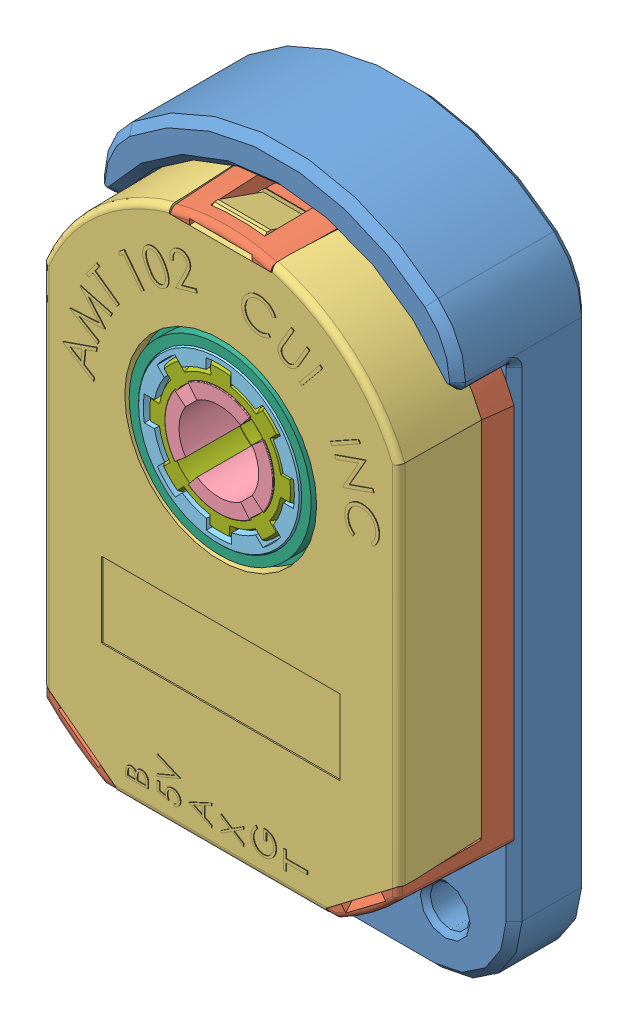
SolidWorks assembly AARL_Puppy_18_01_04_SlabAssembly2, configuration Default. Lengths in mm.
Overall size (36.33 55.03 18.35).
11 component instances, 10 part files, 3 mates.
Components (placement in the parent):
- AARL_Puppy_18_01_04_043-1: AARL_Puppy_18_01_04_043 [Default] at (25.7495 36.0819 36.9303) size (29.26 55.03 13.69)
- CUI_DEVICES_cui_devices_amt102-0048-i6350-s-1: CUI_DEVICES_cui_devices_amt102-0048-i6350-s [Default] at (25.7495 36.0819 46.7201) size (36.33 46.23 9.15)
  - CUI_DEVICES_amt-102-base-rev-k-1: CUI_DEVICES_amt-102-base-rev-k [Default] x (-1 0 0) z (0 0 -1) size (28.83 43.41 9.03)
  - CUI_DEVICES_amt-102-top-cover-rev-h-1: CUI_DEVICES_amt-102-top-cover-rev-h [Default] at (0 0 5.23) x (-1 0 0) z (0 0 -1) size (28.6 43.26 6.55)
  - CUI_DEVICES_amt-sleeve-rev-d(d)-1: CUI_DEVICES_amt-sleeve-rev-d(d) [Default] at (0 0 -2.42) x (0.999996 0.002864 0) z (0 0 1) size (10.79 10.79 7.8)
  - CUI_DEVICES_amt-hub-top-rev-d1-1: CUI_DEVICES_amt-hub-top-rev-d1 [Default] at (0 0 2.13) x (0.999996 0.002864 0) z (0 0 1) size (14 14 5.67)
  - CUI_DEVICES_amt-hub-bottom-rev-b-1: CUI_DEVICES_amt-hub-bottom-rev-b [Default] at (0 0 2.43) x (0.999998 -0.001942 0) z (0 0 1) size (17.3 17.3 3.2)
  - CUI_DEVICES_amt10x-shaft-adaptor-rev-e-1: CUI_DEVICES_amt10x-shaft-adaptor-rev-e [Default] at (0 0 0.03) x (0.999996 0.002864 0) z (0 0 1) size (11.8 11.8 7.8)
  - CUI_DEVICES_receiver-board-1: CUI_DEVICES_receiver-board [Default] at (72.2834 -20.351 3.03) x (-1 0 0) z (0 0 -1) size (26.5 26.62 0.41)
  - CUI_DEVICES_rotor-board-rev f-1: CUI_DEVICES_rotor-board-rev f [Default] at (0 0 2.13) x (0.807874 -0.589355 0) z (0 0 1) size (26 26 0.3)
  - CUI_DEVICES_transmitter-board amt10(amt-102)-1: CUI_DEVICES_transmitter-board amt10(amt-102) [Default] at (19.1596 -17.1102 1.22) x (-1 0 0) z (0 0 -1) size (26.63 38.43 4.41)
Mates (geometry in assembly coordinates):
- Concentric1: concentric anti-aligned: cylinder of AARL_Puppy_18_01_04_043-1 through (25.7495 36.0819 42.9501) axis (0 0 -1) radius 3.2385; cylinder of CUI_DEVICES_cui_devices_amt102-0048-i6350-s-1/CUI_DEVICES_amt-sleeve-rev-d(d)-1 through (25.7495 36.0819 44.3001) axis (0 0 1) radius 3.175
- Coincident1: coincident anti-aligned: plane of AARL_Puppy_18_01_04_043-1 through (25.7495 35.9295 42.9501) normal (0 0 1); plane of CUI_DEVICES_cui_devices_amt102-0048-i6350-s-1/CUI_DEVICES_amt-102-base-rev-k-1 through (25.7495 25.6619 42.9501) normal (0 0 -1)
- Concentric2: concentric aligned: cylinder of AARL_Puppy_18_01_04_043-1 through (36.227 20.3339 36.9303) axis (0 0 1) radius 1.9812; cylinder of CUI_DEVICES_cui_devices_amt102-0048-i6350-s-1/CUI_DEVICES_amt-102-base-rev-k-1 through (36.227 20.3339 42.9501) axis (0 0 1) radius 1.9812
